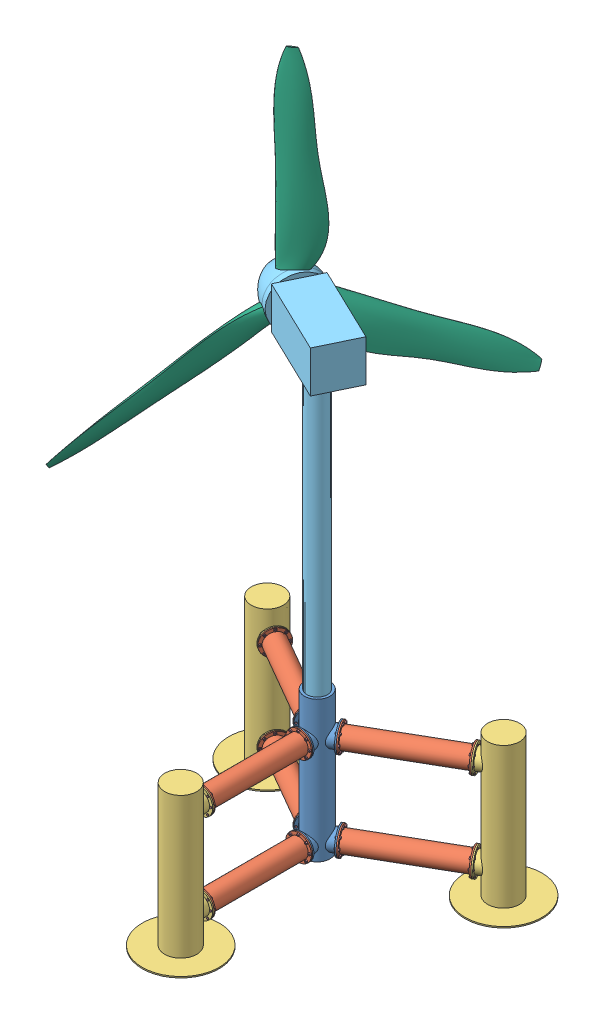
SolidWorks assembly Assem1, configuration Default. Lengths in mm.
Overall size (532.85 1057.03 640.88).
108 component instances, 6 part files, 12 mates.
Components (placement in the parent):
- SparC-1: SparC [Default] at (37.152 54.4751 209.8434) size (66.77 220 57.82)
- Cross-1: Cross [Default] at (37.152 44.4751 236.8434) x (1 0 0) z (0 0 1) size (40 180 154)
- Spar-2: Spar [Default] at (37.152 34.4751 422.8434) x (-1 0 0) z (0 0 -1) size (120 222 120)
- Spar-3: Spar [Default] at (221.6154 34.4751 103.3434) x (0.5 0 0.866025) z (-0.866025 0 0.5) size (120 222 120)
- Spar-4: Spar [Default] at (-147.3114 34.4751 103.3434) x (0.5 0 -0.866025) z (0.866025 0 0.5) size (120 222 120)
- Cross-2: Cross [Default] at (60.5347 44.4751 196.3434) x (-0.5 0 -0.866025) z (0.866025 0 -0.5) size (40 180 154)
- Cross-3: Cross [Default] at (13.7693 44.4751 196.3434) x (-0.5 0 0.866025) z (-0.866025 0 -0.5) size (40 180 154)
- hexalobular socket cheese head_iso-1: hexalobular socket cheese head_iso [ISO 14580 - #2 x 5 x 4.5 - 4.8-N] at (16.3674 231.9751 197.8434) x (0.25 0.866025 -0.433013) z (-0.433013 0.5 0.75) size (3.8 6.55 3.8)
- hexalobular socket cheese head_iso-2: hexalobular socket cheese head_iso [ISO 14580 - #2 x 5 x 4.5 - 4.8-N] at (22.5546 226.8495 187.1269) x (0.482963 0.258819 -0.836516) z (-0.12941 0.965926 0.224144) size (3.8 6.55 3.8)
- hexalobular socket cheese head_iso-3: hexalobular socket cheese head_iso [ISO 14580 - #2 x 5 x 4.5 - 4.8-N] at (25.1174 214.4751 182.688) x (0.433013 -0.5 -0.75) z (0.25 0.866025 -0.433013) size (3.8 6.55 3.8)
- hexalobular socket cheese head_iso-4: hexalobular socket cheese head_iso [ISO 14580 - #2 x 5 x 4.5 - 4.8-N] at (22.5546 202.1008 187.1269) x (0.12941 -0.965926 -0.224144) z (0.482963 0.258819 -0.836516) size (3.8 6.55 3.8)
- hexalobular socket cheese head_iso-5: hexalobular socket cheese head_iso [ISO 14580 - #2 x 5 x 4.5 - 4.8-N] at (16.3674 196.9751 197.8434) x (-0.25 -0.866025 0.433013) z (0.433013 -0.5 -0.75) size (3.8 6.55 3.8)
- hexalobular socket cheese head_iso-6: hexalobular socket cheese head_iso [ISO 14580 - #2 x 5 x 4.5 - 4.8-N] at (10.1802 202.1008 208.5599) x (-0.482963 -0.258819 0.836516) z (0.12941 -0.965926 -0.224144) size (3.8 6.55 3.8)
- hexalobular socket cheese head_iso-7: hexalobular socket cheese head_iso [ISO 14580 - #2 x 5 x 4.5 - 4.8-N] at (7.6174 214.4751 212.9989) x (-0.433013 0.5 0.75) z (-0.25 -0.866025 0.433013) size (3.8 6.55 3.8)
- hexalobular socket cheese head_iso-8: hexalobular socket cheese head_iso [ISO 14580 - #2 x 5 x 4.5 - 4.8-N] at (10.1802 226.8495 208.5599) x (-0.12941 0.965926 0.224144) z (-0.482963 -0.258819 0.836516) size (3.8 6.55 3.8)
- hexalobular socket cheese head_iso-9: hexalobular socket cheese head_iso [ISO 14580 - #2 x 5 x 4.5 - 4.8-N] at (37.152 231.9751 233.8434) x (-0.5 0.866025 0) z (0.866025 0.5 0) size (3.8 6.55 3.8)
- hexalobular socket cheese head_iso-10: hexalobular socket cheese head_iso [ISO 14580 - #2 x 5 x 4.5 - 4.8-N] at (57.9366 231.9751 197.8434) x (0.25 0.866025 0.433013) z (-0.433013 0.5 -0.75) size (3.8 6.55 3.8)
- hexalobular socket cheese head_iso-11: hexalobular socket cheese head_iso [ISO 14580 - #2 x 5 x 4.5 - 4.8-N] at (24.7776 226.8495 233.8434) x (-0.965926 0.258819 0) z (0.258819 0.965926 0) size (3.8 6.55 3.8)
- hexalobular socket cheese head_iso-12: hexalobular socket cheese head_iso [ISO 14580 - #2 x 5 x 4.5 - 4.8-N] at (64.1238 226.8495 208.5599) x (0.482963 0.258819 0.836516) z (-0.12941 0.965926 -0.224144) size (3.8 6.55 3.8)
- hexalobular socket cheese head_iso-13: hexalobular socket cheese head_iso [ISO 14580 - #2 x 5 x 4.5 - 4.8-N] at (19.652 214.4751 233.8434) x (-0.866025 -0.5 0) z (-0.5 0.866025 0) size (3.8 6.55 3.8)
- hexalobular socket cheese head_iso-14: hexalobular socket cheese head_iso [ISO 14580 - #2 x 5 x 4.5 - 4.8-N] at (66.6866 214.4751 212.9989) x (0.433013 -0.5 0.75) z (0.25 0.866025 0.433013) size (3.8 6.55 3.8)
- hexalobular socket cheese head_iso-15: hexalobular socket cheese head_iso [ISO 14580 - #2 x 5 x 4.5 - 4.8-N] at (24.7776 202.1008 233.8434) x (-0.258819 -0.965926 0) z (-0.965926 0.258819 0) size (3.8 6.55 3.8)
- hexalobular socket cheese head_iso-16: hexalobular socket cheese head_iso [ISO 14580 - #2 x 5 x 4.5 - 4.8-N] at (64.1238 202.1008 208.5599) x (0.12941 -0.965926 0.224144) z (0.482963 0.258819 0.836516) size (3.8 6.55 3.8)
- hexalobular socket cheese head_iso-17: hexalobular socket cheese head_iso [ISO 14580 - #2 x 5 x 4.5 - 4.8-N] at (37.152 196.9751 233.8434) x (0.5 -0.866025 0) z (-0.866025 -0.5 0) size (3.8 6.55 3.8)
- hexalobular socket cheese head_iso-18: hexalobular socket cheese head_iso [ISO 14580 - #2 x 5 x 4.5 - 4.8-N] at (57.9366 196.9751 197.8434) x (-0.25 -0.866025 -0.433013) z (0.433013 -0.5 0.75) size (3.8 6.55 3.8)
- hexalobular socket cheese head_iso-19: hexalobular socket cheese head_iso [ISO 14580 - #2 x 5 x 4.5 - 4.8-N] at (49.5264 202.1008 233.8434) x (0.965926 -0.258819 0) z (-0.258819 -0.965926 0) size (3.8 6.55 3.8)
- hexalobular socket cheese head_iso-20: hexalobular socket cheese head_iso [ISO 14580 - #2 x 5 x 4.5 - 4.8-N] at (51.7494 202.1008 187.1269) x (-0.482963 -0.258819 -0.836516) z (0.12941 -0.965926 0.224144) size (3.8 6.55 3.8)
- hexalobular socket cheese head_iso-21: hexalobular socket cheese head_iso [ISO 14580 - #2 x 5 x 4.5 - 4.8-N] at (54.652 214.4751 233.8434) x (0.866025 0.5 0) z (0.5 -0.866025 0) size (3.8 6.55 3.8)
- hexalobular socket cheese head_iso-22: hexalobular socket cheese head_iso [ISO 14580 - #2 x 5 x 4.5 - 4.8-N] at (49.1866 214.4751 182.688) x (-0.433013 0.5 -0.75) z (-0.25 -0.866025 -0.433013) size (3.8 6.55 3.8)
- hexalobular socket cheese head_iso-23: hexalobular socket cheese head_iso [ISO 14580 - #2 x 5 x 4.5 - 4.8-N] at (49.5264 226.8495 233.8434) x (0.258819 0.965926 0) z (0.965926 -0.258819 0) size (3.8 6.55 3.8)
- hexalobular socket cheese head_iso-24: hexalobular socket cheese head_iso [ISO 14580 - #2 x 5 x 4.5 - 4.8-N] at (51.7494 226.8495 187.1269) x (-0.12941 0.965926 -0.224144) z (-0.482963 -0.258819 -0.836516) size (3.8 6.55 3.8)
- hexalobular socket cheese head_iso-25: hexalobular socket cheese head_iso [ISO 14580 - #2 x 5 x 4.5 - 4.8-N] at (-122.1967 231.9751 117.8434) x (0.12941 0.965926 -0.224144) z (0.482963 -0.258819 -0.836516) size (3.8 6.55 3.8)
- hexalobular socket cheese head_iso-26: hexalobular socket cheese head_iso [ISO 14580 - #2 x 5 x 4.5 - 4.8-N] at (-116.0095 226.8495 107.1269) x (0.433013 0.5 -0.75) z (0.25 -0.866025 -0.433013) size (3.8 6.55 3.8)
- hexalobular socket cheese head_iso-27: hexalobular socket cheese head_iso [ISO 14580 - #2 x 5 x 4.5 - 4.8-N] at (-113.4467 214.4751 102.688) x (0.482963 -0.258819 -0.836516) z (-0.12941 -0.965926 0.224144) size (3.8 6.55 3.8)
- hexalobular socket cheese head_iso-28: hexalobular socket cheese head_iso [ISO 14580 - #2 x 5 x 4.5 - 4.8-N] at (-116.0095 202.1008 107.1269) x (0.25 -0.866025 -0.433013) z (-0.433013 -0.5 0.75) size (3.8 6.55 3.8)
- hexalobular socket cheese head_iso-29: hexalobular socket cheese head_iso [ISO 14580 - #2 x 5 x 4.5 - 4.8-N] at (-122.1967 196.9751 117.8434) x (-0.12941 -0.965926 0.224144) z (-0.482963 0.258819 0.836516) size (3.8 6.55 3.8)
- hexalobular socket cheese head_iso-30: hexalobular socket cheese head_iso [ISO 14580 - #2 x 5 x 4.5 - 4.8-N] at (-128.3839 202.1008 128.5599) x (-0.433013 -0.5 0.75) z (-0.25 0.866025 0.433013) size (3.8 6.55 3.8)
- hexalobular socket cheese head_iso-31: hexalobular socket cheese head_iso [ISO 14580 - #2 x 5 x 4.5 - 4.8-N] at (-130.9467 214.4751 132.9989) x (-0.482963 0.258819 0.836516) z (0.12941 0.965926 -0.224144) size (3.8 6.55 3.8)
- hexalobular socket cheese head_iso-32: hexalobular socket cheese head_iso [ISO 14580 - #2 x 5 x 4.5 - 4.8-N] at (-128.3839 226.8495 128.5599) x (-0.25 0.866025 0.433013) z (0.433013 0.5 -0.75) size (3.8 6.55 3.8)
- hexalobular socket cheese head_iso-33: hexalobular socket cheese head_iso [ISO 14580 - #2 x 5 x 4.5 - 4.8-N] at (37.152 231.9751 393.8434) x (-0.258819 0.965926 0) z (-0.965926 -0.258819 0) size (3.8 6.55 3.8)
- hexalobular socket cheese head_iso-34: hexalobular socket cheese head_iso [ISO 14580 - #2 x 5 x 4.5 - 4.8-N] at (196.5007 231.9751 117.8434) x (0.12941 0.965926 0.224144) z (0.482963 -0.258819 0.836516) size (3.8 6.55 3.8)
- hexalobular socket cheese head_iso-35: hexalobular socket cheese head_iso [ISO 14580 - #2 x 5 x 4.5 - 4.8-N] at (24.7776 226.8495 393.8434) x (-0.866025 0.5 0) z (-0.5 -0.866025 0) size (3.8 6.55 3.8)
- hexalobular socket cheese head_iso-36: hexalobular socket cheese head_iso [ISO 14580 - #2 x 5 x 4.5 - 4.8-N] at (202.6879 226.8495 128.5599) x (0.433013 0.5 0.75) z (0.25 -0.866025 0.433013) size (3.8 6.55 3.8)
- hexalobular socket cheese head_iso-37: hexalobular socket cheese head_iso [ISO 14580 - #2 x 5 x 4.5 - 4.8-N] at (19.652 214.4751 393.8434) x (-0.965926 -0.258819 0) z (0.258819 -0.965926 0) size (3.8 6.55 3.8)
- hexalobular socket cheese head_iso-38: hexalobular socket cheese head_iso [ISO 14580 - #2 x 5 x 4.5 - 4.8-N] at (205.2507 214.4751 132.9989) x (0.482963 -0.258819 0.836516) z (-0.12941 -0.965926 -0.224144) size (3.8 6.55 3.8)
- hexalobular socket cheese head_iso-39: hexalobular socket cheese head_iso [ISO 14580 - #2 x 5 x 4.5 - 4.8-N] at (24.7776 202.1008 393.8434) x (-0.5 -0.866025 0) z (0.866025 -0.5 0) size (3.8 6.55 3.8)
- hexalobular socket cheese head_iso-40: hexalobular socket cheese head_iso [ISO 14580 - #2 x 5 x 4.5 - 4.8-N] at (202.6879 202.1008 128.5599) x (0.25 -0.866025 0.433013) z (-0.433013 -0.5 -0.75) size (3.8 6.55 3.8)
- hexalobular socket cheese head_iso-41: hexalobular socket cheese head_iso [ISO 14580 - #2 x 5 x 4.5 - 4.8-N] at (37.152 196.9751 393.8434) x (0.258819 -0.965926 0) z (0.965926 0.258819 0) size (3.8 6.55 3.8)
- hexalobular socket cheese head_iso-42: hexalobular socket cheese head_iso [ISO 14580 - #2 x 5 x 4.5 - 4.8-N] at (196.5007 196.9751 117.8434) x (-0.12941 -0.965926 -0.224144) z (-0.482963 0.258819 -0.836516) size (3.8 6.55 3.8)
- hexalobular socket cheese head_iso-43: hexalobular socket cheese head_iso [ISO 14580 - #2 x 5 x 4.5 - 4.8-N] at (49.5264 202.1008 393.8434) x (0.866025 -0.5 0) z (0.5 0.866025 0) size (3.8 6.55 3.8)
- hexalobular socket cheese head_iso-44: hexalobular socket cheese head_iso [ISO 14580 - #2 x 5 x 4.5 - 4.8-N] at (190.3135 202.1008 107.1269) x (-0.433013 -0.5 -0.75) z (-0.25 0.866025 -0.433013) size (3.8 6.55 3.8)
- hexalobular socket cheese head_iso-45: hexalobular socket cheese head_iso [ISO 14580 - #2 x 5 x 4.5 - 4.8-N] at (54.652 214.4751 393.8434) x (0.965926 0.258819 0) z (-0.258819 0.965926 0) size (3.8 6.55 3.8)
- hexalobular socket cheese head_iso-46: hexalobular socket cheese head_iso [ISO 14580 - #2 x 5 x 4.5 - 4.8-N] at (187.7507 214.4751 102.688) x (-0.482963 0.258819 -0.836516) z (0.12941 0.965926 0.224144) size (3.8 6.55 3.8)
- hexalobular socket cheese head_iso-47: hexalobular socket cheese head_iso [ISO 14580 - #2 x 5 x 4.5 - 4.8-N] at (49.5264 226.8495 393.8434) x (0.5 0.866025 0) z (-0.866025 0.5 0) size (3.8 6.55 3.8)
- hexalobular socket cheese head_iso-48: hexalobular socket cheese head_iso [ISO 14580 - #2 x 5 x 4.5 - 4.8-N] at (190.3135 226.8495 107.1269) x (-0.25 0.866025 -0.433013) z (0.433013 0.5 0.75) size (3.8 6.55 3.8)
- hexalobular socket cheese head_iso-49: hexalobular socket cheese head_iso [ISO 14580 - #2 x 5 x 4.5 - 4.8-N] at (-122.1967 91.9751 117.8434) x (0.12941 0.965926 -0.224144) z (0.482963 -0.258819 -0.836516) size (3.8 6.55 3.8)
- hexalobular socket cheese head_iso-50: hexalobular socket cheese head_iso [ISO 14580 - #2 x 5 x 4.5 - 4.8-N] at (-116.0095 86.8495 107.1269) x (0.433013 0.5 -0.75) z (0.25 -0.866025 -0.433013) size (3.8 6.55 3.8)
- hexalobular socket cheese head_iso-51: hexalobular socket cheese head_iso [ISO 14580 - #2 x 5 x 4.5 - 4.8-N] at (-113.4467 74.4751 102.688) x (0.482963 -0.258819 -0.836516) z (-0.12941 -0.965926 0.224144) size (3.8 6.55 3.8)
- hexalobular socket cheese head_iso-52: hexalobular socket cheese head_iso [ISO 14580 - #2 x 5 x 4.5 - 4.8-N] at (-116.0095 62.1008 107.1269) x (0.25 -0.866025 -0.433013) z (-0.433013 -0.5 0.75) size (3.8 6.55 3.8)
- hexalobular socket cheese head_iso-53: hexalobular socket cheese head_iso [ISO 14580 - #2 x 5 x 4.5 - 4.8-N] at (-122.1967 56.9751 117.8434) x (-0.12941 -0.965926 0.224144) z (-0.482963 0.258819 0.836516) size (3.8 6.55 3.8)
- hexalobular socket cheese head_iso-54: hexalobular socket cheese head_iso [ISO 14580 - #2 x 5 x 4.5 - 4.8-N] at (-128.3839 62.1008 128.5599) x (-0.433013 -0.5 0.75) z (-0.25 0.866025 0.433013) size (3.8 6.55 3.8)
- hexalobular socket cheese head_iso-55: hexalobular socket cheese head_iso [ISO 14580 - #2 x 5 x 4.5 - 4.8-N] at (-130.9467 74.4751 132.9989) x (-0.482963 0.258819 0.836516) z (0.12941 0.965926 -0.224144) size (3.8 6.55 3.8)
- hexalobular socket cheese head_iso-56: hexalobular socket cheese head_iso [ISO 14580 - #2 x 5 x 4.5 - 4.8-N] at (-128.3839 86.8495 128.5599) x (-0.25 0.866025 0.433013) z (0.433013 0.5 -0.75) size (3.8 6.55 3.8)
- hexalobular socket cheese head_iso-57: hexalobular socket cheese head_iso [ISO 14580 - #2 x 5 x 4.5 - 4.8-N] at (37.152 91.9751 393.8434) x (-0.258819 0.965926 0) z (-0.965926 -0.258819 0) size (3.8 6.55 3.8)
- hexalobular socket cheese head_iso-58: hexalobular socket cheese head_iso [ISO 14580 - #2 x 5 x 4.5 - 4.8-N] at (196.5007 91.9751 117.8434) x (0.12941 0.965926 0.224144) z (0.482963 -0.258819 0.836516) size (3.8 6.55 3.8)
- hexalobular socket cheese head_iso-59: hexalobular socket cheese head_iso [ISO 14580 - #2 x 5 x 4.5 - 4.8-N] at (24.7776 86.8495 393.8434) x (-0.866025 0.5 0) z (-0.5 -0.866025 0) size (3.8 6.55 3.8)
- hexalobular socket cheese head_iso-60: hexalobular socket cheese head_iso [ISO 14580 - #2 x 5 x 4.5 - 4.8-N] at (202.6879 86.8495 128.5599) x (0.433013 0.5 0.75) z (0.25 -0.866025 0.433013) size (3.8 6.55 3.8)
- hexalobular socket cheese head_iso-61: hexalobular socket cheese head_iso [ISO 14580 - #2 x 5 x 4.5 - 4.8-N] at (19.652 74.4751 393.8434) x (-0.965926 -0.258819 0) z (0.258819 -0.965926 0) size (3.8 6.55 3.8)
- hexalobular socket cheese head_iso-62: hexalobular socket cheese head_iso [ISO 14580 - #2 x 5 x 4.5 - 4.8-N] at (205.2507 74.4751 132.9989) x (0.482963 -0.258819 0.836516) z (-0.12941 -0.965926 -0.224144) size (3.8 6.55 3.8)
- hexalobular socket cheese head_iso-63: hexalobular socket cheese head_iso [ISO 14580 - #2 x 5 x 4.5 - 4.8-N] at (24.7776 62.1008 393.8434) x (-0.5 -0.866025 0) z (0.866025 -0.5 0) size (3.8 6.55 3.8)
- hexalobular socket cheese head_iso-64: hexalobular socket cheese head_iso [ISO 14580 - #2 x 5 x 4.5 - 4.8-N] at (202.6879 62.1008 128.5599) x (0.25 -0.866025 0.433013) z (-0.433013 -0.5 -0.75) size (3.8 6.55 3.8)
- hexalobular socket cheese head_iso-65: hexalobular socket cheese head_iso [ISO 14580 - #2 x 5 x 4.5 - 4.8-N] at (37.152 56.9751 393.8434) x (0.258819 -0.965926 0) z (0.965926 0.258819 0) size (3.8 6.55 3.8)
- hexalobular socket cheese head_iso-66: hexalobular socket cheese head_iso [ISO 14580 - #2 x 5 x 4.5 - 4.8-N] at (196.5007 56.9751 117.8434) x (-0.12941 -0.965926 -0.224144) z (-0.482963 0.258819 -0.836516) size (3.8 6.55 3.8)
- hexalobular socket cheese head_iso-67: hexalobular socket cheese head_iso [ISO 14580 - #2 x 5 x 4.5 - 4.8-N] at (49.5264 62.1008 393.8434) x (0.866025 -0.5 0) z (0.5 0.866025 0) size (3.8 6.55 3.8)
- hexalobular socket cheese head_iso-68: hexalobular socket cheese head_iso [ISO 14580 - #2 x 5 x 4.5 - 4.8-N] at (190.3135 62.1008 107.1269) x (-0.433013 -0.5 -0.75) z (-0.25 0.866025 -0.433013) size (3.8 6.55 3.8)
- hexalobular socket cheese head_iso-69: hexalobular socket cheese head_iso [ISO 14580 - #2 x 5 x 4.5 - 4.8-N] at (54.652 74.4751 393.8434) x (0.965926 0.258819 0) z (-0.258819 0.965926 0) size (3.8 6.55 3.8)
- hexalobular socket cheese head_iso-70: hexalobular socket cheese head_iso [ISO 14580 - #2 x 5 x 4.5 - 4.8-N] at (187.7507 74.4751 102.688) x (-0.482963 0.258819 -0.836516) z (0.12941 0.965926 0.224144) size (3.8 6.55 3.8)
- hexalobular socket cheese head_iso-71: hexalobular socket cheese head_iso [ISO 14580 - #2 x 5 x 4.5 - 4.8-N] at (49.5264 86.8495 393.8434) x (0.5 0.866025 0) z (-0.866025 0.5 0) size (3.8 6.55 3.8)
- hexalobular socket cheese head_iso-72: hexalobular socket cheese head_iso [ISO 14580 - #2 x 5 x 4.5 - 4.8-N] at (190.3135 86.8495 107.1269) x (-0.25 0.866025 -0.433013) z (0.433013 0.5 0.75) size (3.8 6.55 3.8)
- hexalobular socket cheese head_iso-73: hexalobular socket cheese head_iso [ISO 14580 - #2 x 5 x 4.5 - 4.8-N] at (16.3674 91.9751 197.8434) x (0.25 0.866025 -0.433013) z (-0.433013 0.5 0.75) size (3.8 6.55 3.8)
- hexalobular socket cheese head_iso-74: hexalobular socket cheese head_iso [ISO 14580 - #2 x 5 x 4.5 - 4.8-N] at (22.5546 86.8495 187.1269) x (0.482963 0.258819 -0.836516) z (-0.12941 0.965926 0.224144) size (3.8 6.55 3.8)
- hexalobular socket cheese head_iso-75: hexalobular socket cheese head_iso [ISO 14580 - #2 x 5 x 4.5 - 4.8-N] at (25.1174 74.4751 182.688) x (0.433013 -0.5 -0.75) z (0.25 0.866025 -0.433013) size (3.8 6.55 3.8)
- hexalobular socket cheese head_iso-76: hexalobular socket cheese head_iso [ISO 14580 - #2 x 5 x 4.5 - 4.8-N] at (22.5546 62.1008 187.1269) x (0.12941 -0.965926 -0.224144) z (0.482963 0.258819 -0.836516) size (3.8 6.55 3.8)
- hexalobular socket cheese head_iso-77: hexalobular socket cheese head_iso [ISO 14580 - #2 x 5 x 4.5 - 4.8-N] at (16.3674 56.9751 197.8434) x (-0.25 -0.866025 0.433013) z (0.433013 -0.5 -0.75) size (3.8 6.55 3.8)
- hexalobular socket cheese head_iso-78: hexalobular socket cheese head_iso [ISO 14580 - #2 x 5 x 4.5 - 4.8-N] at (10.1802 62.1008 208.5599) x (-0.482963 -0.258819 0.836516) z (0.12941 -0.965926 -0.224144) size (3.8 6.55 3.8)
- hexalobular socket cheese head_iso-79: hexalobular socket cheese head_iso [ISO 14580 - #2 x 5 x 4.5 - 4.8-N] at (7.6174 74.4751 212.9989) x (-0.433013 0.5 0.75) z (-0.25 -0.866025 0.433013) size (3.8 6.55 3.8)
- hexalobular socket cheese head_iso-80: hexalobular socket cheese head_iso [ISO 14580 - #2 x 5 x 4.5 - 4.8-N] at (10.1802 86.8495 208.5599) x (-0.12941 0.965926 0.224144) z (-0.482963 -0.258819 0.836516) size (3.8 6.55 3.8)
- hexalobular socket cheese head_iso-81: hexalobular socket cheese head_iso [ISO 14580 - #2 x 5 x 4.5 - 4.8-N] at (37.152 91.9751 233.8434) x (-0.5 0.866025 0) z (0.866025 0.5 0) size (3.8 6.55 3.8)
- hexalobular socket cheese head_iso-82: hexalobular socket cheese head_iso [ISO 14580 - #2 x 5 x 4.5 - 4.8-N] at (57.9366 91.9751 197.8434) x (0.25 0.866025 0.433013) z (-0.433013 0.5 -0.75) size (3.8 6.55 3.8)
- hexalobular socket cheese head_iso-83: hexalobular socket cheese head_iso [ISO 14580 - #2 x 5 x 4.5 - 4.8-N] at (24.7776 86.8495 233.8434) x (-0.965926 0.258819 0) z (0.258819 0.965926 0) size (3.8 6.55 3.8)
- hexalobular socket cheese head_iso-84: hexalobular socket cheese head_iso [ISO 14580 - #2 x 5 x 4.5 - 4.8-N] at (64.1238 86.8495 208.5599) x (0.482963 0.258819 0.836516) z (-0.12941 0.965926 -0.224144) size (3.8 6.55 3.8)
- hexalobular socket cheese head_iso-85: hexalobular socket cheese head_iso [ISO 14580 - #2 x 5 x 4.5 - 4.8-N] at (19.652 74.4751 233.8434) x (-0.866025 -0.5 0) z (-0.5 0.866025 0) size (3.8 6.55 3.8)
- hexalobular socket cheese head_iso-86: hexalobular socket cheese head_iso [ISO 14580 - #2 x 5 x 4.5 - 4.8-N] at (66.6866 74.4751 212.9989) x (0.433013 -0.5 0.75) z (0.25 0.866025 0.433013) size (3.8 6.55 3.8)
- hexalobular socket cheese head_iso-87: hexalobular socket cheese head_iso [ISO 14580 - #2 x 5 x 4.5 - 4.8-N] at (24.7776 62.1008 233.8434) x (-0.258819 -0.965926 0) z (-0.965926 0.258819 0) size (3.8 6.55 3.8)
- hexalobular socket cheese head_iso-88: hexalobular socket cheese head_iso [ISO 14580 - #2 x 5 x 4.5 - 4.8-N] at (64.1238 62.1008 208.5599) x (0.12941 -0.965926 0.224144) z (0.482963 0.258819 0.836516) size (3.8 6.55 3.8)
- hexalobular socket cheese head_iso-89: hexalobular socket cheese head_iso [ISO 14580 - #2 x 5 x 4.5 - 4.8-N] at (37.152 56.9751 233.8434) x (0.5 -0.866025 0) z (-0.866025 -0.5 0) size (3.8 6.55 3.8)
- hexalobular socket cheese head_iso-90: hexalobular socket cheese head_iso [ISO 14580 - #2 x 5 x 4.5 - 4.8-N] at (57.9366 56.9751 197.8434) x (-0.25 -0.866025 -0.433013) z (0.433013 -0.5 0.75) size (3.8 6.55 3.8)
- hexalobular socket cheese head_iso-91: hexalobular socket cheese head_iso [ISO 14580 - #2 x 5 x 4.5 - 4.8-N] at (49.5264 62.1008 233.8434) x (0.965926 -0.258819 0) z (-0.258819 -0.965926 0) size (3.8 6.55 3.8)
- hexalobular socket cheese head_iso-92: hexalobular socket cheese head_iso [ISO 14580 - #2 x 5 x 4.5 - 4.8-N] at (51.7494 62.1008 187.1269) x (-0.482963 -0.258819 -0.836516) z (0.12941 -0.965926 0.224144) size (3.8 6.55 3.8)
- hexalobular socket cheese head_iso-93: hexalobular socket cheese head_iso [ISO 14580 - #2 x 5 x 4.5 - 4.8-N] at (54.652 74.4751 233.8434) x (0.866025 0.5 0) z (0.5 -0.866025 0) size (3.8 6.55 3.8)
- hexalobular socket cheese head_iso-94: hexalobular socket cheese head_iso [ISO 14580 - #2 x 5 x 4.5 - 4.8-N] at (49.1866 74.4751 182.688) x (-0.433013 0.5 -0.75) z (-0.25 -0.866025 -0.433013) size (3.8 6.55 3.8)
- hexalobular socket cheese head_iso-95: hexalobular socket cheese head_iso [ISO 14580 - #2 x 5 x 4.5 - 4.8-N] at (49.5264 86.8495 233.8434) x (0.258819 0.965926 0) z (0.965926 -0.258819 0) size (3.8 6.55 3.8)
- hexalobular socket cheese head_iso-96: hexalobular socket cheese head_iso [ISO 14580 - #2 x 5 x 4.5 - 4.8-N] at (51.7494 86.8495 187.1269) x (-0.12941 0.965926 -0.224144) z (-0.482963 -0.258819 -0.836516) size (3.8 6.55 3.8)
- turbie-1: turbie [Default] at (597.4326 189.9821 239.572) x (-0.43366 0 0.901077) z (-0.901077 0 -0.43366) size (614.99 815.03 200)
  - Tower1-1: Tower1 [Default] at (216.1836 84.493 517.7478) size (80 522.5 200)
  - blade-1: blade [Default] at (217.4586 599.493 597.2478) x (0.866025 0 0.5) z (0 1 0) size (73.31 29.13 300.04)
  - blade-2: blade [Default] at (187.4003 551.8472 597.2478) x (-0.433013 0.75 0.5) z (-0.866025 -0.5 0) size (73.31 29.13 300.04)
  - blade-3: blade [Default] at (243.6919 549.6388 597.2478) x (-0.433013 -0.75 0.5) z (0.866025 -0.5 0) size (73.31 29.13 300.04)
Mates (geometry in assembly coordinates):
- Coincident1: coincident anti-aligned: plane of Spar-1 through (37.152 214.4751 236.8434) normal (0 0 1); plane of Cross-1 through (37.152 214.4751 236.8434) normal (0 0 -1)
- Concentric1: concentric aligned: cylinder of Spar-1 through (24.7776 226.8495 236.8434) axis (0 0 -1) radius 1.5; cylinder of Cross-1 through (24.7776 226.8495 238.8434) axis (0 0 -1) radius 1.5
- Concentric2: concentric aligned: cylinder of Spar-1 through (49.5264 86.8495 236.8434) axis (0 0 -1) radius 1.5; cylinder of Cross-1 through (49.5264 86.8495 238.8434) axis (0 0 -1) radius 1.5
- Coincident2: coincident anti-aligned: plane of Cross-1 through (37.152 214.4751 390.8434) normal (0 0 1); plane of Spar-2 through (37.152 214.4751 390.8434) normal (0 0 -1)
- Concentric3: concentric anti-aligned: cylinder of Cross-1 through (49.5264 226.8495 390.8434) axis (0 0 -1) radius 1.5; cylinder of Spar-2 through (49.5264 226.8495 390.8434) axis (0 0 1) radius 1.5
- Concentric4: concentric anti-aligned: cylinder of Cross-1 through (37.152 91.9751 390.8434) axis (0 0 -1) radius 1.5; cylinder of Spar-2 through (37.152 91.9751 390.8434) axis (0 0 1) radius 1.5
- Concentric6: concentric aligned: cylinder of Cross-3 through (12.0373 231.9751 195.3434) axis (0.866025 0 0.5) radius 1.5; cylinder of hexalobular socket cheese head_iso-1 through (16.3674 231.9751 197.8434) axis (0.866025 0 0.5) radius 1.3
- Coincident4: coincident anti-aligned: plane of Cross-3 through (12.0373 214.4751 195.3434) normal (-0.866025 0 -0.5); plane of hexalobular socket cheese head_iso-1 through (12.3223 232.9624 194.8498) normal (0.866025 0 0.5)
- Concentric7: concentric anti-aligned: cylinder of Cross-3 through (-119.5986 231.9751 119.3434) axis (0.866025 0 0.5) radius 1.5; cylinder of hexalobular socket cheese head_iso-25 through (-122.1967 231.9751 117.8434) axis (-0.866025 0 -0.5) radius 1.3
- Coincident5: coincident anti-aligned: plane of Cross-3 through (-117.8665 214.4751 120.3434) normal (0.866025 0 0.5); plane of hexalobular socket cheese head_iso-25 through (-117.719 233.0763 120.0879) normal (-0.866025 0 -0.5)
- Concentric8: concentric aligned: cylinder of SparC-1 through (37.152 274.4751 209.8434) axis (0 -1 0) radius 20; cylinder of turbie-1/Tower1-1 through (37.152 724.4751 209.8434) axis (0 -1 0) radius 16
- Coincident6: coincident anti-aligned: plane of SparC-1 through (37.152 274.4751 209.8434) normal (0 1 0); plane of turbie-1/Tower1-1 through (37.152 274.4751 209.8434) normal (0 -1 0)
